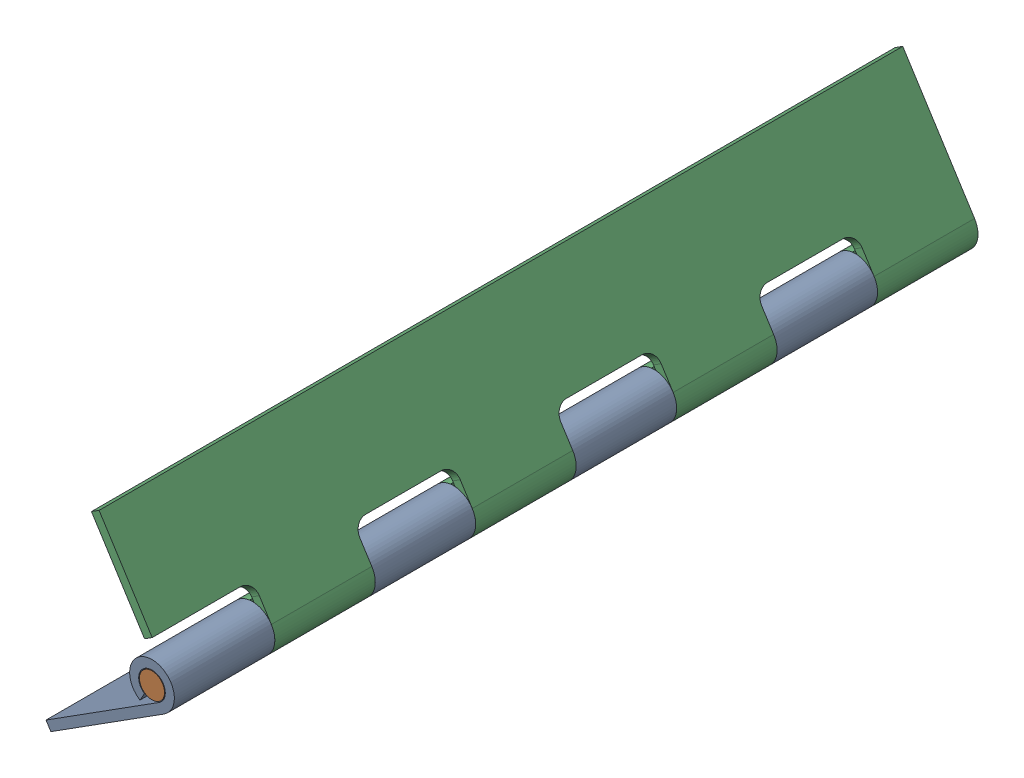
SolidWorks assembly FE-00004-08_, configuration Default. Lengths in mm.
Overall size (39.43 54.56 203.2).
3 component instances, 2 part files, 0 mates.
Components (placement in the parent):
- FE-00004-08A_-1: FE-00004-08A_ [Default] at (15.9508 35.5603 3.2618) x (0.535841 -0.844319 0) z (0 0 1) size (11.3 39.53 203.2)
- FE-00004-08C_-1: FE-00004-08C_ [Default] at (45.8136 41.8195 3.2618) x (0.999872 0.016022 0) z (0 0 1) size (6.35 6.35 203.2)
- FE-00004-08A_-2: FE-00004-08A_ [Default] at (24.7489 74.9242 206.4618) x (0.844319 0.535841 0) z (0 0 -1) size (11.3 39.53 203.2)
